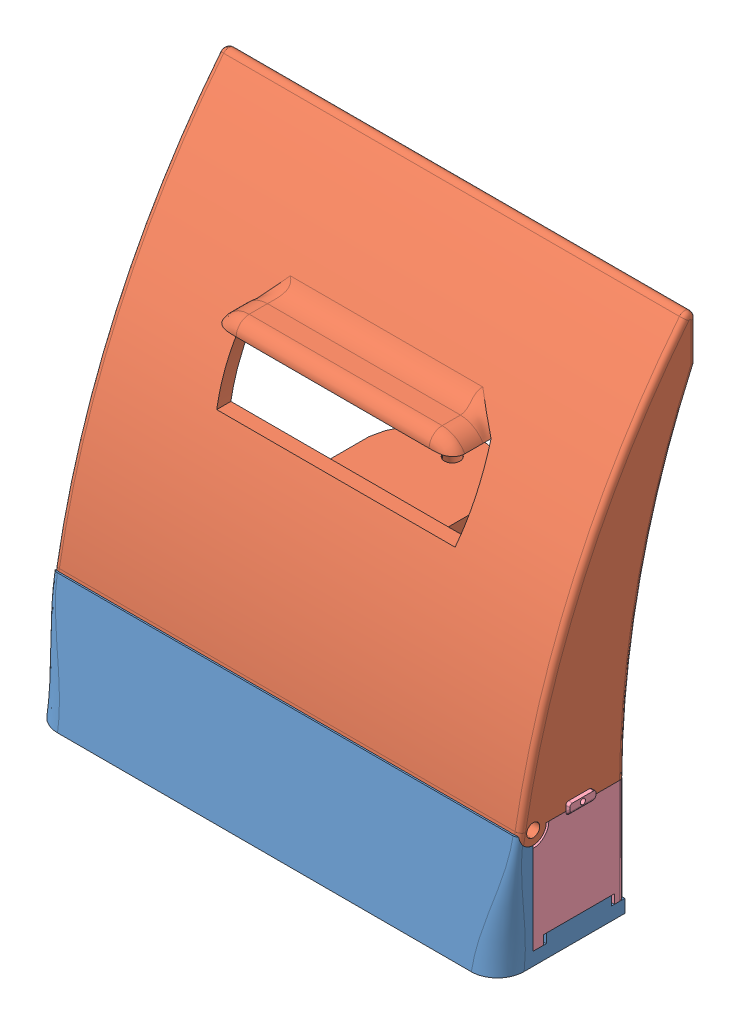
SolidWorks assembly front assembly 2, configuration Default. Lengths in mm.
Overall size (181 187.95 76.47).
4 component instances, 4 part files, 9 mates.
Components (placement in the parent):
- Foldable front base 2-1: Foldable front base 2 [Default] at (158.3211 77.8479 159.546) size (179.15 52.01 49.18)
- foldable front flap 2-1: foldable front flap 2 [Default] at (69.3211 122.8479 151.0232) x (-1 0 0) z (0 0 -1) size (178.61 145.94 74.18)
- Foldable front side flap right 2-1: Foldable front side flap right 2 [Default] at (-17.1789 86.3479 110.946) x (0 0 1) z (-1 0 0) size (35 43 8.5)
- Foldable front side flap left 2-1: Foldable front side flap left 2 [Default] at (155.8211 86.3479 145.946) x (0 0 -1) z (1 0 0) size (35 43 8.5)
Mates (geometry in assembly coordinates):
- Concentric1: concentric: cylinder of Foldable front base 2-1 through (-19.6789 122.8479 145.946) axis (1 0 0) radius 2.5; cylinder of foldable front flap 2-1 through (158.3211 122.8479 145.946) axis (-1 0 0) radius 2.5
- Distance1: distance = 1 mm: plane of foldable front flap 2-1 through (-14.6789 122.8479 145.946) normal (1 0 0); plane of Foldable front base 2-1 through (-13.6789 122.8479 145.946) normal (-1 0 0)
- Concentric2: concentric: cylinder of Foldable front base 2-1 through (154.8211 86.3479 140.946) axis (0 0 -1) radius 2.5; cylinder of Foldable front side flap left 2-1 through (154.8211 86.3479 114.946) axis (0 0 -1) radius 2.5
- Distance2: distance = 1 mm: plane of Foldable front base 2-1 through (158.3211 77.8479 115.946) normal (0 0 -1); plane of Foldable front side flap left 2-1 through (155.8211 86.3479 114.946) normal (0 0 1)
- Concentric3: concentric: cylinder of Foldable front base 2-1 through (-16.1789 86.3479 140.946) axis (0 0 -1) radius 2.5; cylinder of Foldable front side flap right 2-1 through (-16.1789 86.3479 114.946) axis (0 0 -1) radius 2.5
- Distance3: distance = 1 mm: plane of Foldable front side flap right 2-1 through (-17.1789 86.3479 141.946) normal (0 0 -1); plane of Foldable front base 2-1 through (158.3211 77.8479 140.946) normal (0 0 1)
- Coincident1: coincident: plane of Foldable front base 2-1 through (158.3211 122.8479 159.546) normal (1 0 0); plane of Foldable front side flap left 2-1 through (158.3211 86.3479 145.946) normal (1 0 0)
- Coincident2: coincident: plane of Foldable front base 2-1 through (-19.6789 122.8479 159.546) normal (-1 0 0); plane of Foldable front side flap right 2-1 through (-19.6789 86.3479 110.946) normal (-1 0 0)
- Coincident3: coincident: plane of foldable front flap 2-1 through (-14.6789 122.8479 140.946) normal (0 -1 0); plane of Foldable front side flap right 2-1 through (-19.6789 122.8479 110.946) normal (0 1 0)
